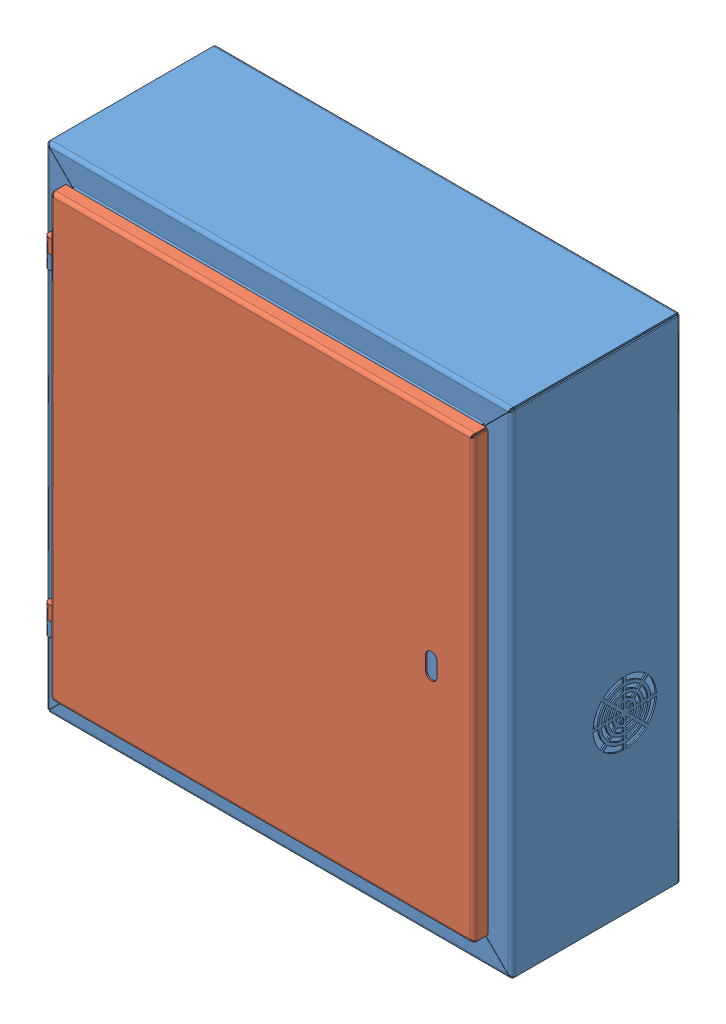
SolidWorks assembly elctric_panel_box, configuration Default. Lengths in mm.
Overall size (330.01 350 132).
2 component instances, 2 part files, 3 mates.
Components (placement in the parent):
- ee-1: ee [Default] at (-31.3812 10.5842 -34.6329) size (330.01 350 128)
- door-1: door [Default] at (-31.3812 12.0842 96.3671) x (-1 0 0) z (0 0 -1) size (308 312 10)
Mates (geometry in assembly coordinates):
- Concentric1: concentric aligned: cylinder of ee-1 through (-186.3812 127.5842 90.3671) axis (0 -1 0) radius 1.5; cylinder of door-1 through (-186.3812 127.5842 90.3671) axis (0 -1 0) radius 1.525
- Coincident1: coincident anti-aligned: plane of ee-1 through (-189.3812 125.5842 93.3671) normal (0 1 0); plane of door-1 through (-189.3812 125.5842 87.3671) normal (0 -1 0)
- LimitAngle1: limit planar angle = 0 rad aligned: plane of ee-1 through (-31.3812 10.5842 85.3671) normal (0 0 1); plane of door-1 through (-31.3812 12.0842 97.3671) normal (0 0 1)
